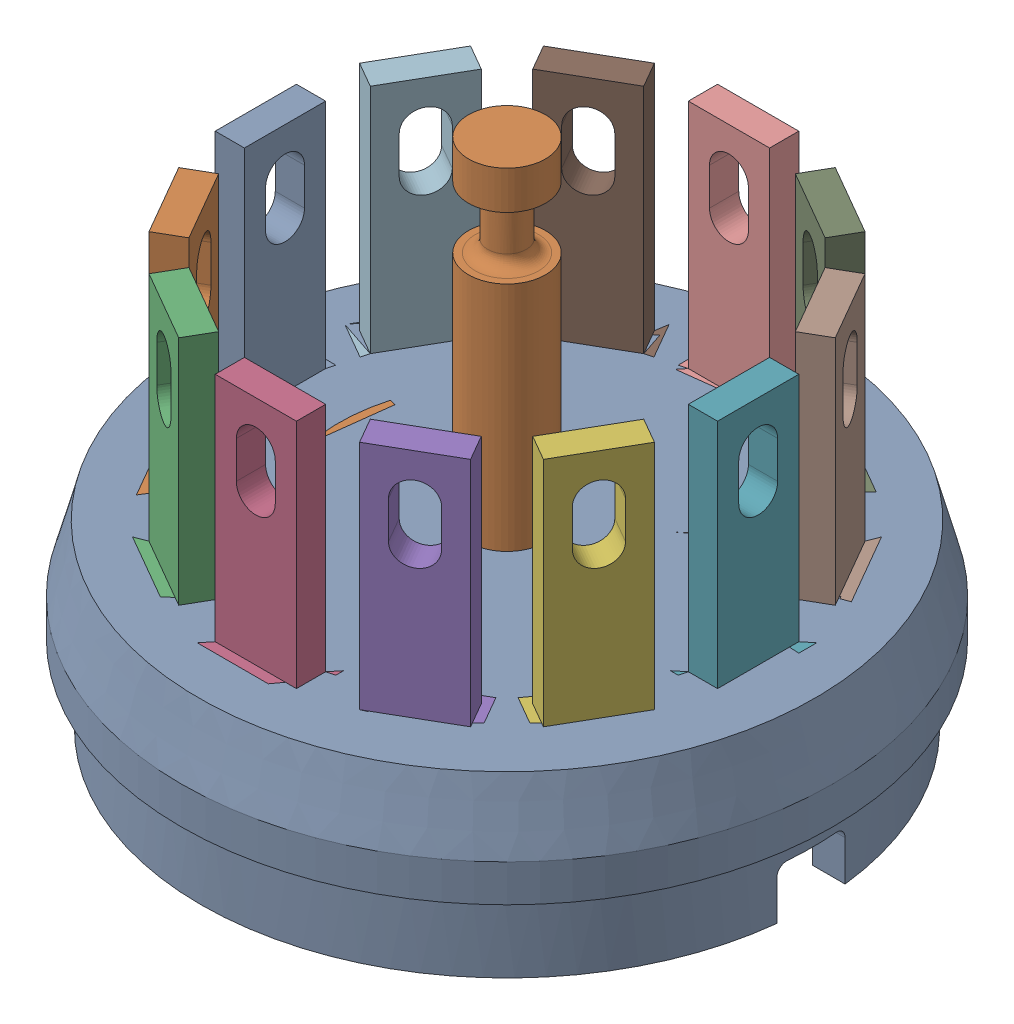
SolidWorks assembly 58ZZ3040-5_ASM, configuration Default. Lengths in mm.
Overall size (13.36 10.5 13.36).
14 component instances, 3 part files, 0 mates.
Components (placement in the parent):
- 58ZZ3040-X_PLASTIC-1: 58ZZ3040-X_PLASTIC [Default] at origin size (13.36 3.7 13.36)
- 50C3495-5-B-001-1: 50C3495-5-B-001 [Default] at (-4.2014 0.696 2.4257) x (0.5 0 0.866025) z (0.866025 0 -0.5) size (2 6.75 1.01)
- 50C3495-5-B-001-2: 50C3495-5-B-001 [Default] at (-2.4257 0.696 4.2014) x (0.866025 0 0.5) z (0.5 0 -0.866025) size (2 6.75 1.01)
- 50C3495-5-B-001-3: 50C3495-5-B-001 [Default] at (0 0.696 4.8514) x (1 0 0) z (0 0 -1) size (2 6.75 1.01)
- 50C3495-5-B-001-4: 50C3495-5-B-001 [Default] at (2.4257 0.696 4.2014) x (0.866025 0 -0.5) z (-0.5 0 -0.866025) size (2 6.75 1.01)
- 50C3495-5-B-001-5: 50C3495-5-B-001 [Default] at (4.2014 0.696 2.4257) x (0.5 0 -0.866025) z (-0.866025 0 -0.5) size (2 6.75 1.01)
- 50C3495-5-B-001-6: 50C3495-5-B-001 [Default] at (4.8514 0.696 0) x (0 0 -1) z (-1 0 0) size (2 6.75 1.01)
- 50C3495-5-B-001-7: 50C3495-5-B-001 [Default] at (4.2014 0.696 -2.4257) x (-0.5 0 -0.866025) z (-0.866025 0 0.5) size (2 6.75 1.01)
- 50C3495-5-B-001-8: 50C3495-5-B-001 [Default] at (2.4257 0.696 -4.2014) x (-0.866025 0 -0.5) z (-0.5 0 0.866025) size (2 6.75 1.01)
- 50C3495-5-B-001-9: 50C3495-5-B-001 [Default] at (0 0.696 -4.8514) x (-1 0 0) z (0 0 1) size (2 6.75 1.01)
- 50C3495-5-B-001-10: 50C3495-5-B-001 [Default] at (-2.4257 0.696 -4.2014) x (-0.866025 0 0.5) z (0.5 0 0.866025) size (2 6.75 1.01)
- 50C3495-5-B-001-11: 50C3495-5-B-001 [Default] at (-4.2014 0.696 -2.4257) x (-0.5 0 0.866025) z (0.866025 0 0.5) size (2 6.75 1.01)
- 50C3495-5-B-001-12: 50C3495-5-B-001 [Default] at (-4.8514 0.696 0) x (0 0 1) z (1 0 0) size (2 6.75 1.01)
- 58C3026-10-1: 58C3026-10 [Default] at (0 0.3302 0) size (7.16 8.59 7.16)
